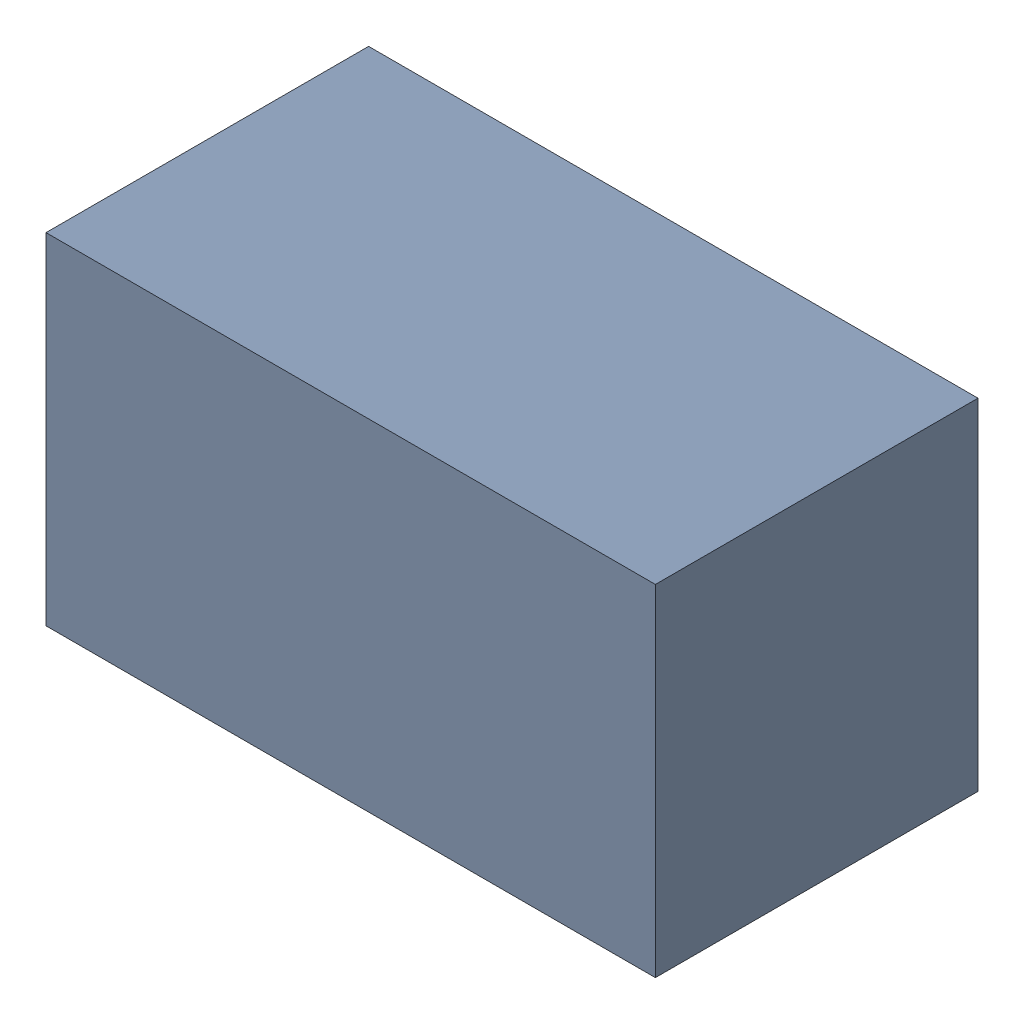
SolidWorks assembly R204, configuration Standard. Lengths in mm.
Overall size (1.7 0.95 0.9).
2 component instances, 1 part files, 0 mates.
Components (placement in the parent):
- 885541288-1: 885541288 [Standard] at (12.1 -11.4 0) size (1.7 0.95 0.9)
  - Extruded_10-1: Extruded_10 [Standard] at origin size (1.7 0.95 0.9)
